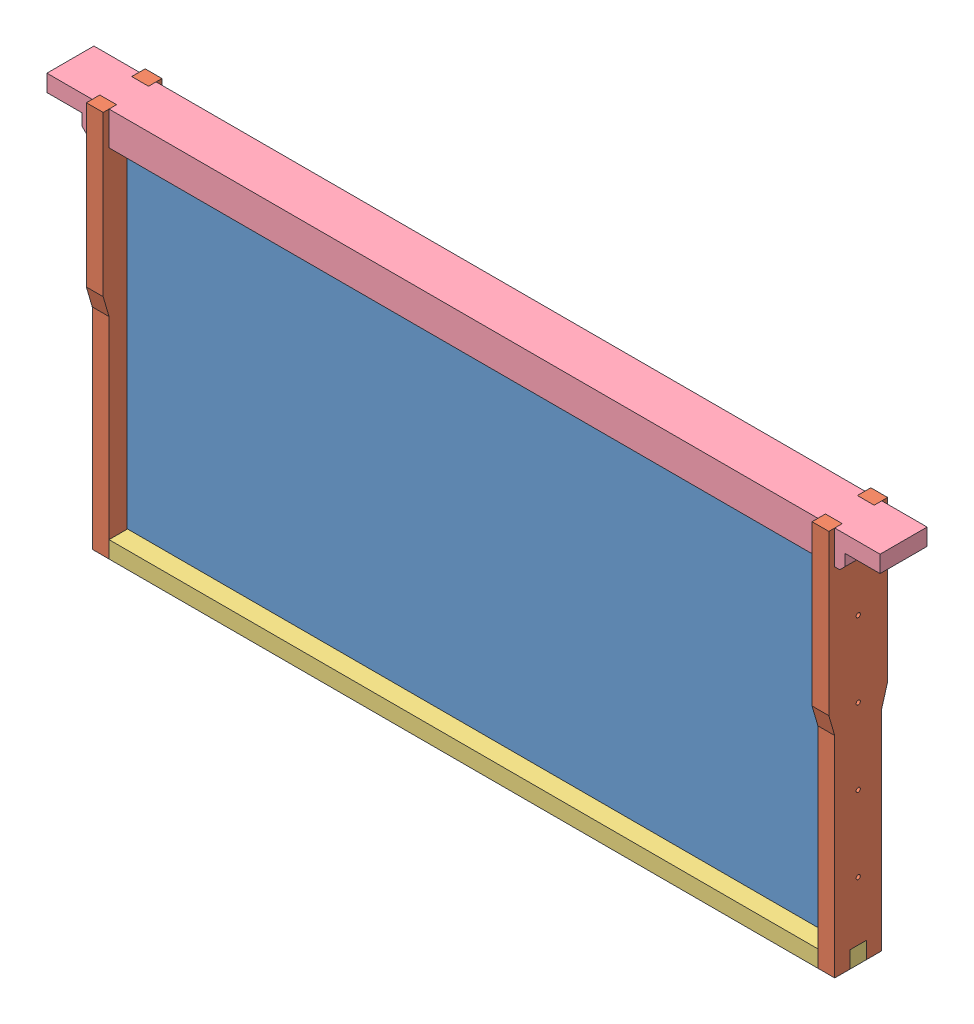
SolidWorks assembly Quadre, configuration Predeterminado. Lengths in mm.
Overall size (490 232 35).
5 component instances, 4 part files, 9 mates.
Components (placement in the parent):
- Panell_cera-2: Panell_cera [Predeterminado] at (91.8201 -83.2348 -411.1686) size (420 200 1)
- Peça_lateral_quadre-5: Peça_lateral_quadre [Predeterminado] at (303.2949 -82.9282 -414.3695) size (10 232 35)
- Peça_lateral_quadre-6: Peça_lateral_quadre [Predeterminado] at (-128.7051 -82.9282 -414.3695) size (10 232 35)
- Peça_inferior_quadre-3: Peça_inferior_quadre [Predeterminado] at (92.2949 -193.9282 -414.3695) size (442 10 28)
- Peça_superior_quadre-3: Peça_superior_quadre [Predeterminado] at (92.2949 38.0718 -414.3695) x (-1 0 0) z (0 0 1) size (490 20 28)
Mates (geometry in assembly coordinates):
- Coincidente5: coincident aligned: plane of Peça_lateral_quadre-5 through (313.2949 -82.9282 -414.3695) normal (1 0 0); plane of Peça_inferior_quadre-3 through (313.2949 -183.9282 -419.3695) normal (1 0 0)
- Coincidente6: coincident aligned: plane of Peça_lateral_quadre-5 through (313.2949 -193.9282 -428.3695) normal (0 0 -1); plane of Peça_inferior_quadre-3 through (-118.7051 -183.9282 -428.3695) normal (0 0 -1)
- Coincidente7: coincident aligned: plane of Peça_lateral_quadre-5 through (313.2949 -193.9282 -419.3695) normal (0 -1 0); plane of Peça_inferior_quadre-3 through (92.2949 -193.9282 -414.3695) normal (0 -1 0)
- Coincidente8: coincident aligned: plane of Peça_lateral_quadre-6 through (-118.7051 -193.9282 -428.3695) normal (0 0 -1); plane of Peça_inferior_quadre-3 through (-118.7051 -183.9282 -428.3695) normal (0 0 -1)
- Coincidente9: coincident aligned: plane of Peça_lateral_quadre-6 through (-128.7051 -82.9282 -414.3695) normal (-1 0 0); plane of Peça_inferior_quadre-3 through (-128.7051 -183.9282 -409.3695) normal (-1 0 0)
- Coincidente11: coincident aligned: plane of Peça_lateral_quadre-6 through (-118.7051 -193.9282 -419.3695) normal (0 -1 0); plane of Peça_inferior_quadre-3 through (92.2949 -193.9282 -414.3695) normal (0 -1 0)
- Coincidente12: coincident aligned: plane of Peça_lateral_quadre-5 through (313.2949 38.0718 -404.8695) normal (0 1 0); plane of Peça_superior_quadre-3 through (92.2949 38.0718 -414.3695) normal (0 1 0)
- Coincidente13: coincident anti-aligned: plane of Peça_lateral_quadre-5 through (313.2949 38.0718 -423.8695) normal (0 0 1); plane of Peça_superior_quadre-3 through (303.2949 28.0718 -423.8695) normal (0 0 -1)
- Coincidente14: coincident anti-aligned: plane of Peça_lateral_quadre-6 through (-118.7051 -82.9282 -414.3695) normal (1 0 0); plane of Peça_superior_quadre-3 through (-118.7051 18.0718 -400.3695) normal (-1 0 0)
